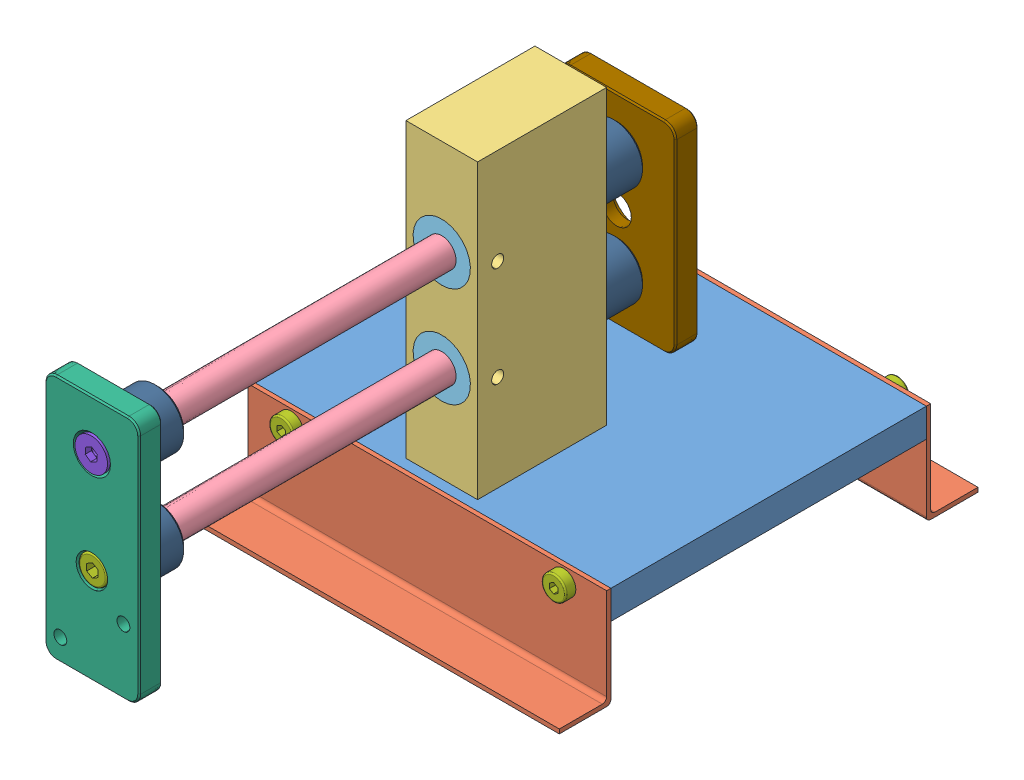
SolidWorks assembly cum_s3, configuration Default. Lengths in mm.
Overall size (125 137 246.72).
26 component instances, 10 part files, 59 mates.
Components (placement in the parent):
- tam_de-1: tam_de [Default] at (55.7373 162.4347 98.3877) size (125 10 110)
- khoi_do-1: khoi_do [Default] at (118.2373 137.4347 153.3877) x (0 0 1) z (0 -1 0) size (18 125 35)
- khoi_do-2: khoi_do [Default] at (-6.7627 137.4347 43.3877) x (0 0 -1) z (0 -1 0) size (18 125 35)
- con_truot-4: con_truot [Default] at (43.2373 223.4347 127.3877) x (0 0 1) z (0 1 0) size (45 25 102)
- chot_dan_huong-1: chot_dan_huong [Default] at (55.7373 240.9347 263.8877) x (0.818617 0.57434 0) z (-0.57434 0.818617 0) size (10 175 10)
- bat_lot-3: bat_lot [Default] at (55.7373 240.9347 149.8877) x (0.167613 0.985853 0) z (-0.985853 0.167613 0) size (20 10 20)
- bat_lot-4: bat_lot [Default] at (55.7373 205.9347 149.8877) x (0.167613 0.985853 0) z (-0.985853 0.167613 0) size (20 10 20)
- bat_lot-5: bat_lot [Default] at (55.7373 240.9347 104.8877) x (-0.554759 0.832011 0) z (0.832011 0.554759 0) size (20 10 20)
- bat_lot-6: bat_lot [Default] at (55.7373 205.9347 104.8877) x (0.395512 -0.918461 0) z (-0.918461 -0.395512 0) size (20 10 20)
- chot_dan_huong-2: chot_dan_huong [Default] at (55.7373 205.9347 263.8877) x (0.187291 -0.982304 0) z (0.982304 0.187291 0) size (10 175 10)
- ban_canh_truoc-1: ban_canh_truoc [Default] at (55.7373 215.4347 263.8877) x (1 0 0) z (0 -1 0) size (33 8 86)
- socket head thin cap screw_din-14: socket head thin cap screw_din [DIN 7984 - M5 x 8 --- 5.6N] at (8.2373 167.4347 38.3877) x (0 0 1) z (-1 0 0) size (11.5 8.5 8.5)
- socket head thin cap screw_din-16: socket head thin cap screw_din [DIN 7984 - M5 x 8 --- 5.6N] at (8.2373 167.4347 158.3877) x (0 0 -1) z (1 0 0) size (11.5 8.5 8.5)
- socket head thin cap screw_din-17: socket head thin cap screw_din [DIN 7984 - M5 x 8 --- 5.6N] at (103.2373 167.4347 158.3877) x (0 0 -1) z (1 0 0) size (11.5 8.5 8.5)
- socket head thin cap screw_din-18: socket head thin cap screw_din [DIN 7984 - M5 x 8 --- 5.6N] at (63.2373 164.6347 109.3877) x (0 1 0) z (0 0 1) size (11.5 8.5 8.5)
- socket head thin cap screw_din-19: socket head thin cap screw_din [DIN 7984 - M5 x 8 --- 5.6N] at (48.2373 164.6347 145.3877) x (0 1 0) z (0 0 1) size (11.5 8.5 8.5)
- socket head thin cap screw_din-22: socket head thin cap screw_din [DIN 7984 - M5 x 8 --- 5.6N] at (103.2373 167.4347 38.3877) x (0 0 1) z (-1 0 0) size (11.5 8.5 8.5)
- socket head thin cap screw_din-23: socket head thin cap screw_din [DIN 7984 - M6 x 10 --- 7N] at (55.7373 205.9347 81.0877) x (0 0 1) z (-1 0 0) size (14 10 10)
- socket head thin cap screw_din-24: socket head thin cap screw_din [DIN 7984 - M6 x 10 --- 7N] at (55.7373 205.6984 271.6877) x (0 0 -1) z (1 0 0) size (14 10 10)
- socket csink head cap screw 10642_din-2: socket csink head cap screw 10642_din [EN ISO 10642 - M6 x 8 - 8N] at (55.7373 240.9347 80.6677) x (0 0 1) z (-0.997818 -0.066017 0) size (8 11.34 11.34)
- socket csink head cap screw 10642_din-3: socket csink head cap screw 10642_din [EN ISO 10642 - M6 x 8 - 8N] at (55.7373 240.9347 272.1077) x (0 0 -1) z (0.996151 -0.087658 0) size (8 11.34 11.34)
- s3_ban_canh_sau-1: s3_ban_canh_sau [Default] at (55.7373 223.4347 88.8877) x (-1 0 0) z (0 -1 0) size (41 8 70)
- bac_chan-1: bac_chan [Default] at (55.7373 240.9347 248.8877) x (-0.999622 -0.027501 0) z (-0.027501 0.999622 0) size (20 15 20)
- bac_chan-2: bac_chan [Default] at (55.7373 205.9347 248.8877) x (1 0 0) z (0 -1 0) size (20 15 20)
- bac_chan-3: bac_chan [Default] at (55.7373 240.9347 103.8877) x (1 0 0) z (0 1 0) size (20 15 20)
- bac_chan-4: bac_chan [Default] at (55.7373 205.9347 103.8877) x (1 0 0) z (0 1 0) size (20 15 20)
Mates (geometry in assembly coordinates):
- Parallel1: parallel aligned: plane of tam_de-1 through (-6.7627 172.4347 153.3877) normal (0 0 1); plane of khoi_do-1 through (-6.7627 172.4347 154.8877) normal (0 0 1)
- Concentric1: concentric aligned: cylinder of tam_de-1 through (8.2373 167.4347 153.3877) axis (0 0 1) radius 2.1; circle of khoi_do-1
- Concentric2: concentric aligned: circle of tam_de-1; circle of khoi_do-1
- Coincident1: coincident anti-aligned: plane of tam_de-1 through (-6.7627 172.4347 153.3877) normal (0 0 1); plane of khoi_do-1 through (-6.7627 137.4347 153.3877) normal (0 0 -1)
- Parallel2: parallel anti-aligned: plane of tam_de-1 through (-6.7627 172.4347 43.3877) normal (0 0 -1); plane of khoi_do-2 through (118.2373 137.4347 43.3877) normal (0 0 1)
- Concentric3: concentric aligned: circle of tam_de-1; cylinder of khoi_do-2 through (8.2373 167.4347 43.3877) axis (0 0 -1) radius 2.75
- Parallel3: parallel aligned: plane of tam_de-1 through (55.7373 172.4347 98.3877) normal (0 1 0); plane of khoi_do-2 through (118.2373 172.4347 43.3877) normal (0 1 0)
- Coincident2: coincident anti-aligned: plane of tam_de-1 through (-6.7627 172.4347 43.3877) normal (0 0 -1); plane of khoi_do-2 through (118.2373 137.4347 43.3877) normal (0 0 1)
- Parallel8: parallel anti-aligned: plane of tam_de-1 through (55.7373 172.4347 98.3877) normal (0 1 0); plane of con_truot-4 through (68.2373 172.4347 104.8877) normal (0 -1 0)
- Concentric8: concentric anti-aligned: circle of tam_de-1; circle of con_truot-4
- Concentric9: concentric anti-aligned: circle of tam_de-1; cylinder of con_truot-4 through (48.2373 172.4347 145.3877) axis (0 -1 0) radius 2.1
- Coincident6: coincident anti-aligned: plane of tam_de-1 through (55.7373 172.4347 98.3877) normal (0 1 0); plane of con_truot-4 through (68.2373 172.4347 104.8877) normal (0 -1 0)
- Concentric12: concentric anti-aligned: circle of con_truot-4; circle of bat_lot-3
- Coincident9: coincident anti-aligned: plane of con_truot-4 through (55.7373 240.9347 147.8877) normal (0 0 1); plane of bat_lot-3 through (55.7373 240.9347 147.8877) normal (0 0 -1)
- Concentric13: concentric anti-aligned: cylinder of con_truot-4 through (55.7373 205.9347 178.8877) axis (0 0 -1) radius 6; cylinder of bat_lot-4 through (55.7373 205.9347 139.8877) axis (0 0 1) radius 6
- Coincident10: coincident aligned: plane of con_truot-4 through (68.2373 274.4347 149.8877) normal (0 0 1); plane of bat_lot-4 through (55.7373 205.9347 149.8877) normal (0 0 1)
- Concentric14: concentric aligned: cylinder of con_truot-4 through (55.7373 240.9347 178.8877) axis (0 0 -1) radius 6; cylinder of bat_lot-5 through (55.7373 240.9347 114.8877) axis (0 0 -1) radius 6
- Coincident11: coincident aligned: plane of con_truot-4 through (68.2373 274.4347 104.8877) normal (0 0 -1); plane of bat_lot-5 through (55.7373 240.9347 104.8877) normal (0 0 -1)
- Concentric15: concentric aligned: cylinder of con_truot-4 through (55.7373 205.9347 178.8877) axis (0 0 -1) radius 6; cylinder of bat_lot-6 through (55.7373 205.9347 114.8877) axis (0 0 -1) radius 6
- Coincident13: coincident anti-aligned: plane of con_truot-4 through (55.7373 205.9347 106.8877) normal (0 0 -1); plane of bat_lot-6 through (55.7373 205.9347 106.8877) normal (0 0 1)
- Concentric16: concentric anti-aligned: circle of chot_dan_huong-1; circle of bat_lot-3
- Concentric17: concentric anti-aligned: circle of bat_lot-4; circle of chot_dan_huong-2
- Parallel10: parallel aligned: plane of con_truot-4 through (68.2373 274.4347 149.8877) normal (0 0 1); plane of ban_canh_truoc-1 through (55.7373 215.4347 271.8877) normal (0 0 1)
- Concentric18: concentric aligned: cylinder of chot_dan_huong-2 through (55.7373 205.9347 263.8877) axis (0 0 1) radius 2.5; circle of ban_canh_truoc-1
- Concentric19: concentric anti-aligned: circle of chot_dan_huong-1; circle of ban_canh_truoc-1
- Coincident14: coincident aligned: plane of chot_dan_huong-1 through (55.7373 240.9347 263.8877) normal (0 0 1); circle of ban_canh_truoc-1
- Coincident15: coincident aligned: circle of chot_dan_huong-2; plane of ban_canh_truoc-1 through (55.7373 215.4347 263.8877) normal (0 0 -1)
- Concentric37: concentric aligned: cylinder of khoi_do-2 through (8.2373 167.4347 43.3877) axis (0 0 -1) radius 2.75; cylinder of socket head thin cap screw_din-14 through (8.2373 167.4347 6.6377) axis (0 0 -1) radius 4.25
- Coincident28: coincident anti-aligned: plane of khoi_do-2 through (118.2373 172.4347 41.8877) normal (0 0 -1); plane of socket head thin cap screw_din-14 through (8.2373 171.6847 41.8877) normal (0 0 1)
- Concentric39: concentric aligned: cylinder of khoi_do-1 through (8.2373 167.4347 153.3877) axis (0 0 1) radius 2.75; cylinder of socket head thin cap screw_din-16 through (8.2373 167.4347 190.1377) axis (0 0 1) radius 4.25
- Coincident30: coincident anti-aligned: plane of khoi_do-1 through (-6.7627 172.4347 154.8877) normal (0 0 1); plane of socket head thin cap screw_din-16 through (8.2373 171.6847 154.8877) normal (0 0 -1)
- Concentric40: concentric aligned: cylinder of khoi_do-1 through (103.2373 167.4347 153.3877) axis (0 0 1) radius 2.75; cylinder of socket head thin cap screw_din-17 through (103.2373 167.4347 190.1377) axis (0 0 1) radius 4.25
- Coincident31: coincident anti-aligned: plane of khoi_do-1 through (-6.7627 172.4347 154.8877) normal (0 0 1); plane of socket head thin cap screw_din-17 through (103.2373 171.6847 154.8877) normal (0 0 -1)
- Concentric41: concentric aligned: cylinder of tam_de-1 through (63.2373 172.4347 109.3877) axis (0 -1 0) radius 2.75; cylinder of socket head thin cap screw_din-18 through (63.2373 132.8847 109.3877) axis (0 -1 0) radius 4.25
- Coincident32: coincident anti-aligned: plane of tam_de-1 through (63.2373 168.1347 109.3877) normal (0 -1 0); plane of socket head thin cap screw_din-18 through (58.9873 168.1347 109.3877) normal (0 1 0)
- Concentric42: concentric aligned: cylinder of tam_de-1 through (48.2373 172.4347 145.3877) axis (0 -1 0) radius 2.75; cylinder of socket head thin cap screw_din-19 through (48.2373 132.8847 145.3877) axis (0 -1 0) radius 4.25
- Coincident33: coincident anti-aligned: plane of tam_de-1 through (48.2373 168.1347 145.3877) normal (0 -1 0); plane of socket head thin cap screw_din-19 through (43.9873 168.1347 145.3877) normal (0 1 0)
- Concentric451: concentric aligned: cylinder of khoi_do-2 through (103.2373 167.4347 43.3877) axis (0 0 -1) radius 2.75; cylinder of socket head thin cap screw_din-22 through (103.2373 167.4347 6.6377) axis (0 0 -1) radius 4.25
- Coincident361: coincident anti-aligned: plane of khoi_do-2 through (118.2373 172.4347 41.8877) normal (0 0 -1); plane of socket head thin cap screw_din-22 through (103.2373 171.6847 41.8877) normal (0 0 1)
- Concentric47: concentric aligned: cylinder of ban_canh_truoc-1 through (55.7373 205.6984 267.6877) axis (0 0 1) radius 5.5; cylinder of socket head thin cap screw_din-24 through (55.7373 205.6984 303.4377) axis (0 0 1) radius 5
- Coincident38: coincident anti-aligned: plane of ban_canh_truoc-1 through (55.7373 205.6984 267.6877) normal (0 0 1); plane of socket head thin cap screw_din-24 through (55.7373 210.6984 267.6877) normal (0 0 -1)
- Coincident40: coincident aligned: cone of ban_canh_truoc-1 through (55.7373 240.9347 268.6877) axis (0 0 -1); cylinder of socket csink head cap screw 10642_din-3 through (55.7373 240.9347 271.0577) axis (0 0 -1) radius 785.3982
- Parallel12: parallel aligned: plane of con_truot-4 through (68.2373 274.4347 104.8877) normal (0 0 -1); plane of s3_ban_canh_sau-1 through (55.7373 223.4347 80.8877) normal (0 0 -1)
- Concentric452: concentric aligned: circle of chot_dan_huong-2; circle of s3_ban_canh_sau-1
- Parallel13: parallel aligned: plane of con_truot-4 through (68.2373 223.4347 127.3877) normal (1 0 0); plane of s3_ban_canh_sau-1 through (76.2373 188.4347 80.8877) normal (1 0 0)
- Coincident362: coincident anti-aligned: plane of chot_dan_huong-1 through (55.7373 240.9347 88.8877) normal (0 0 -1); plane of s3_ban_canh_sau-1 through (55.7373 223.4347 88.8877) normal (0 0 1)
- Concentric453: concentric anti-aligned: cylinder of socket csink head cap screw 10642_din-2 through (55.7373 240.9347 80.6677) axis (0 0 -1) radius 3; cylinder of s3_ban_canh_sau-1 through (55.7373 240.9347 80.8877) axis (0 0 1) radius 3.3
- Coincident363: coincident aligned: cylinder of socket csink head cap screw 10642_din-2 through (55.7373 240.9347 81.7177) axis (0 0 1) radius 785.3982; cylinder of s3_ban_canh_sau-1 through (55.7373 240.9347 84.0877) axis (0 0 1) radius 785.3982
- Concentric454: concentric aligned: cylinder of chot_dan_huong-2 through (55.7373 205.9347 88.8877) axis (0 0 -1) radius 2.5; cylinder of socket head thin cap screw_din-23 through (55.7373 205.9347 49.3377) axis (0 0 -1) radius 3
- Coincident364: coincident anti-aligned: plane of socket head thin cap screw_din-23 through (55.7373 210.9347 85.0877) normal (0 0 1); plane of s3_ban_canh_sau-1 through (55.7373 205.9347 85.0877) normal (0 0 -1)
- Concentric456: concentric anti-aligned: cylinder of chot_dan_huong-1 through (55.7373 240.9347 88.8877) axis (0 0 1) radius 5; cylinder of bac_chan-1 through (55.7373 240.9347 263.8877) axis (0 0 -1) radius 5
- Coincident366: coincident anti-aligned: plane of ban_canh_truoc-1 through (55.7373 215.4347 263.8877) normal (0 0 -1); plane of bac_chan-1 through (55.7373 240.9347 263.8877) normal (0 0 1)
- Concentric457: concentric anti-aligned: cylinder of chot_dan_huong-2 through (55.7373 205.9347 88.8877) axis (0 0 1) radius 5; circle of bac_chan-2
- Coincident367: coincident anti-aligned: plane of ban_canh_truoc-1 through (55.7373 215.4347 263.8877) normal (0 0 -1); plane of bac_chan-2 through (55.7373 205.9347 263.8877) normal (0 0 1)
- Concentric458: concentric anti-aligned: cylinder of chot_dan_huong-1 through (55.7373 240.9347 88.8877) axis (0 0 1) radius 5; circle of bac_chan-3
- Coincident368: coincident anti-aligned: plane of s3_ban_canh_sau-1 through (55.7373 223.4347 88.8877) normal (0 0 1); plane of bac_chan-3 through (55.7373 240.9347 88.8877) normal (0 0 -1)
- Concentric459: concentric anti-aligned: cylinder of chot_dan_huong-2 through (55.7373 205.9347 88.8877) axis (0 0 1) radius 5; circle of bac_chan-4
- Coincident369: coincident anti-aligned: plane of s3_ban_canh_sau-1 through (55.7373 223.4347 88.8877) normal (0 0 1); plane of bac_chan-4 through (55.7373 205.9347 88.8877) normal (0 0 -1)
- LimitDistance3: limit distance = 1 mm anti-aligned: plane of bac_chan-3 through (55.7373 240.9347 103.8877) normal (0 0 1); plane of con_truot-4 through (68.2373 274.4347 104.8877) normal (0 0 -1)
